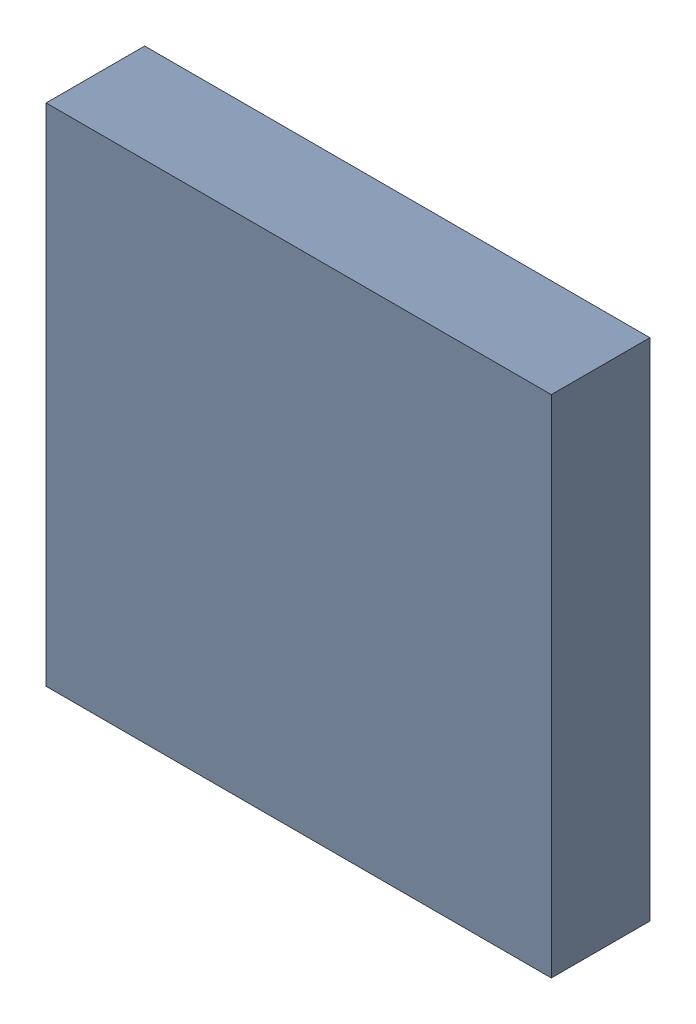
SolidWorks assembly U1, configuration ﾃﾞﾌｫﾙﾄ. Lengths in mm.
Overall size (4.1 4.1 0.8).
2 component instances, 1 part files, 0 mates.
Components (placement in the parent):
- 689261920-1: 689261920 [ﾃﾞﾌｫﾙﾄ] at (14.75 31.25 0) size (4.1 4.1 0.8)
  - Extruded_36-1: Extruded_36 [ﾃﾞﾌｫﾙﾄ] at origin size (4.1 4.1 0.8)
